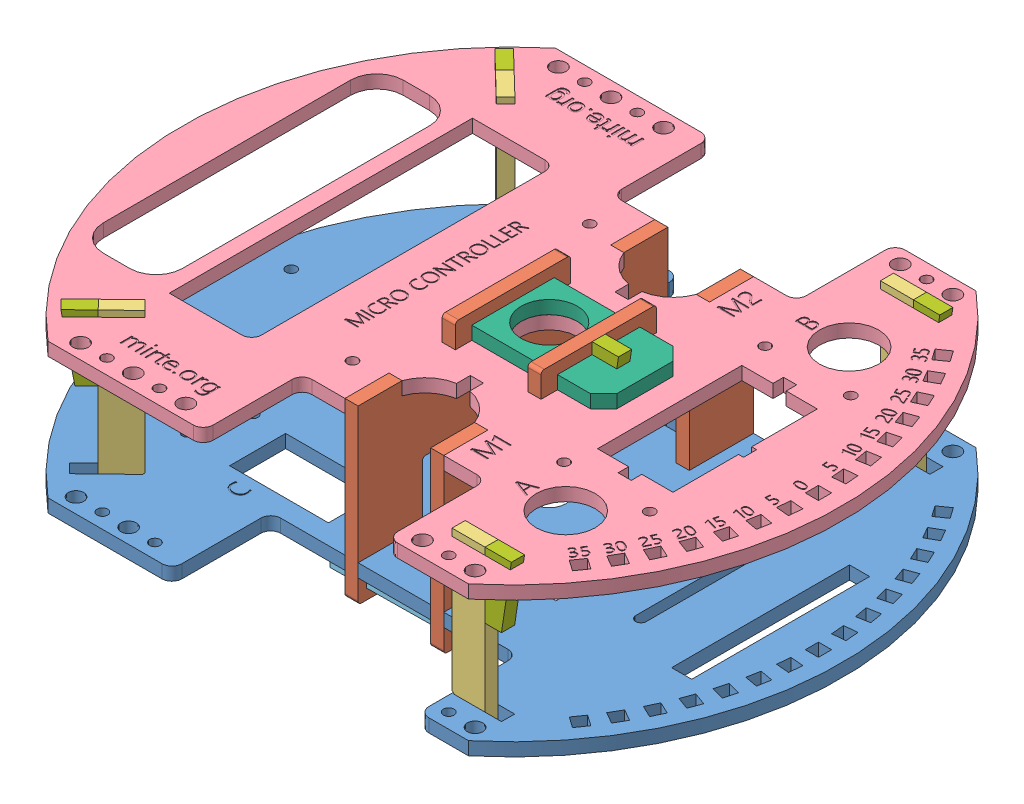
SolidWorks assembly Frame Only, configuration Default. Lengths in mm.
Overall size (200 59.7 154).
16 component instances, 7 part files, 47 mates.
Components (placement in the parent):
- LAYER 1 New-1: LAYER 1 New [Default] at origin size (200 4 154)
- Motor frame 2-1: Motor frame 2 [Default] at (22.3044 -7.1 47) x (0 0 -1) z (0 -1 0) size (94 4 59.7)
- Motor frame 2-2: Motor frame 2 [Default] at (-3.6956 -7.1 47) x (0 0 -1) z (0 -1 0) size (94 4 59.7)
- Slide spacer-1: Slide spacer [Default] at (-58.0581 21.9 53.2858) x (0.71934 0 -0.694658) z (0.694658 0 0.71934) size (10 50.4 4)
- Slide spacer-2: Slide spacer [Default] at (-55.2795 21.9 -56.1631) x (0.71934 0 0.694658) z (-0.694658 0 0.71934) size (10 50.4 4)
- Slide spacer-3: Slide spacer [Default] at (48.8044 22.1644 -63) x (-1 0 0) z (0 0 -1) size (10 50.4 4)
- Slide spacer-5: Slide spacer [Default] at (48.8044 22.1644 67) x (-1 0 0) z (0 0 -1) size (10 50.4 4)
- LAYER 2 new-1: LAYER 2 new [Default] at (-116.6328 -60.1337 -160.0612) size (200 4 154)
- Houder-1: Houder [Default] at (-10.6956 -4 -35.4978) size (45 4 9)
- Houder-2: Houder [Default] at (-10.6956 -4 44.4978) size (45 4 9)
- Pen Hole Lock-1: Pen Hole Lock [Default] at (-3.6956 45.2 12.5) size (44 4 25)
- WIG_single-1: WIG_single [Default] at (26.3044 32.6 2) x (-1 0 0) z (0 0 -1) size (8 20 4)
- WIG_single-2: WIG_single [Default] at (58.8044 27.3644 -63) x (-1 0 0) z (0 0 -1) size (8 20 4)
- WIG_single-3: WIG_single [Default] at (58.8044 27.3644 67) x (-1 0 0) z (0 0 -1) size (8 20 4)
- WIG_single-4: WIG_single [Default] at (-62.4729 27.1 -63.1097) x (0.71934 0 0.694658) z (-0.694658 0 0.71934) size (8 20 4)
- WIG_single-5: WIG_single [Default] at (-65.2515 27.1 60.2324) x (0.71934 0 -0.694658) z (0.694658 0 0.71934) size (8 20 4)
Mates (geometry in assembly coordinates):
- Coincident9: coincident aligned: plane of Motor frame 2-1 through (26.3044 -7.1 -47) normal (0 0 -1); plane of Motor frame 2-2 through (0.3044 -7.1 -47) normal (0 0 -1)
- Coincident10: coincident aligned: plane of Motor frame 2-1 through (26.3044 22 47) normal (0 -1 0); plane of Motor frame 2-2 through (0.3044 22 47) normal (0 -1 0)
- Coincident11: coincident anti-aligned: plane of LAYER 1 New-1 through (0 4 0) normal (0 1 0); plane of Motor frame 2-1 through (26.3044 4 47) normal (0 -1 0)
- Coincident12: coincident aligned: plane of LAYER 1 New-1 through (0 0 47) normal (0 0 1); plane of Motor frame 2-2 through (0.3044 -7.1 47) normal (0 0 1)
- Coincident13: coincident anti-aligned: plane of LAYER 1 New-1 through (0.3044 -14.5602 47.64) normal (-1 0 0); plane of Motor frame 2-2 through (0.3044 -7.1 47) normal (1 0 0)
- Coincident14: coincident anti-aligned: plane of LAYER 1 New-1 through (22.3044 -14.5602 47.64) normal (1 0 0); plane of Motor frame 2-1 through (22.3044 -7.1 47) normal (-1 0 0)
- Coincident29: coincident anti-aligned: plane of LAYER 1 New-1 through (-59.7394 -13.9983 60.47) normal (-0.71934 0 0.694658); plane of Slide spacer-1 through (-59.7394 21.9 60.47) normal (0.71934 0 -0.694658)
- Coincident30: coincident: line of LAYER 1 New-1 through (-66.9328 4 67.4166) axis (0.71934 0 -0.694658); plane of Slide spacer-1 through (-55.2795 21.9 56.1631) normal (0.694658 0 0.71934)
- Coincident31: coincident: point of LAYER 1 New-1; line of Slide spacer-1 through (-59.7394 0 60.47) axis (-0.694658 0 -0.71934)
- Coincident32: coincident anti-aligned: line of LAYER 1 New-1 through (-59.7394 0 -60.47) axis (-0.694658 0 0.71934); line of Slide spacer-2 through (-62.5181 0 -57.5927) axis (0.694658 0 -0.71934)
- Coincident33: coincident anti-aligned: plane of LAYER 1 New-1 through (-62.5181 -13.9983 -57.5927) normal (-0.71934 0 -0.694658); plane of Slide spacer-2 through (-62.5181 21.9 -57.5927) normal (0.71934 0 0.694658)
- Coincident34: coincident: line of LAYER 1 New-1 through (-69.7115 4 -64.5392) axis (0.71934 0 0.694658); plane of Slide spacer-2 through (-58.0581 21.9 -53.2858) normal (-0.694658 0 0.71934)
- Coincident35: coincident aligned: plane of LAYER 1 New-1 through (48.8044 0 0) normal (-1 0 0); plane of Slide spacer-5 through (48.8044 22.1644 63) normal (-1 0 0)
- Coincident36: coincident anti-aligned: plane of LAYER 1 New-1 through (53.8044 -13.9983 67) normal (0 0 -1); plane of Slide spacer-5 through (48.8044 22.1644 67) normal (0 0 1)
- Coincident39: coincident: plane of LAYER 1 New-1 through (0 0 0) normal (0 -1 0); line of Slide spacer-5 through (49.54 0 63) axis (0 0 1)
- Coincident40: coincident aligned: plane of LAYER 1 New-1 through (48.8044 0 0) normal (-1 0 0); plane of Slide spacer-3 through (48.8044 22.1644 -67) normal (-1 0 0)
- Coincident42: coincident anti-aligned: plane of LAYER 1 New-1 through (53.8044 -13.9983 -67) normal (0 0 1); plane of Slide spacer-3 through (48.8044 22.1644 -67) normal (0 0 -1)
- Coincident43: coincident: plane of LAYER 1 New-1 through (0 0 0) normal (0 -1 0); line of Slide spacer-3 through (49.54 0 -67) axis (0 0 1)
- Coincident44: coincident anti-aligned: plane of Motor frame 2-1 through (22.3044 -7.1 47) normal (-1 0 0); plane of LAYER 2 new-1 through (22.3044 45.2 -160.0612) normal (1 0 0)
- Coincident45: coincident anti-aligned: plane of Motor frame 2-1 through (26.3044 -7.1 17.5) normal (0 0 1); plane of LAYER 2 new-1 through (-116.6328 45.2 17.5) normal (0 0 -1)
- Coincident46: coincident anti-aligned: plane of Motor frame 2-1 through (26.3044 41.2 -47) normal (0 1 0); plane of LAYER 2 new-1 through (-116.6328 41.2 -160.0612) normal (0 -1 0)
- Coincident47: coincident: line of Motor frame 2-2 through (-3.6956 -4.1 44.42) axis (0 1 0); plane of Houder-2 through (34.3044 0 43.9978) normal (0.01111 0 0.999938)
- Parallel1: parallel aligned: plane of Motor frame 2-2 through (-3.6956 -7.1 47) normal (-1 0 0); plane of Houder-2 through (-10.6956 0 35.4978) normal (-1 0 0)
- Coincident49: coincident anti-aligned: plane of LAYER 1 New-1 through (0 0 0) normal (0 -1 0); plane of Houder-2 through (-10.6956 0 44.4978) normal (0 1 0)
- Distance1: distance = 7 mm aligned: plane of Houder-2 through (-10.6956 0 35.4978) normal (-1 0 0); plane of Motor frame 2-2 through (-3.6956 -7.1 47) normal (-1 0 0)
- Coincident51: coincident aligned: plane of Houder-1 through (-10.6956 0 -44.4978) normal (-1 0 0); plane of Houder-2 through (-10.6956 0 35.4978) normal (-1 0 0)
- Coincident52: coincident: line of Motor frame 2-2 through (-3.6956 -4.1 -44.42) axis (0 1 0); plane of Houder-1 through (-10.6956 0 -44.4978) normal (0.01111 0 -0.999938)
- Coincident53: coincident anti-aligned: plane of LAYER 1 New-1 through (0 0 0) normal (0 -1 0); plane of Houder-1 through (-10.6956 0 -35.4978) normal (0 1 0)
- Coincident54: coincident: line of Motor frame 2-1 through (26.3044 49.2 -12.5) axis (0 0 1); plane of Pen Hole Lock-1 through (-3.6956 49.2 12.5) normal (0 1 0)
- Coincident55: coincident anti-aligned: plane of Motor frame 2-1 through (26.3044 -7.1 -12.5) normal (0 0 1); plane of Pen Hole Lock-1 through (-3.6956 49.2 -12.5) normal (0 0 -1)
- Coincident56: coincident aligned: plane of Motor frame 2-1 through (26.3044 -7.1 47) normal (1 0 0); plane of Pen Hole Lock-1 through (26.3044 49.2 2) normal (1 0 0)
- Coincident57: coincident anti-aligned: plane of Pen Hole Lock-1 through (26.3044 49.2 2) normal (1 0 0); plane of WIG_single-1 through (26.3044 52.6 -2) normal (-1 0 0)
- Coincident58: coincident anti-aligned: plane of Pen Hole Lock-1 through (26.3044 49.2 2) normal (0 0 -1); plane of WIG_single-1 through (26.3044 32.6 2) normal (0 0 1)
- Coincident59: coincident aligned: plane of Motor frame 2-1 through (26.3044 52.6 47) normal (0 1 0); plane of WIG_single-1 through (34.3044 52.6 -2) normal (0 1 0)
- Coincident60: coincident anti-aligned: plane of Slide spacer-1 through (-62.4729 21.9 63.1097) normal (-0.71934 0 0.694658); plane of WIG_single-5 through (-62.4729 47.1 63.1097) normal (0.71934 0 -0.694658)
- Coincident61: coincident aligned: plane of Slide spacer-1 through (-55.2795 21.9 56.1631) normal (0.694658 0 0.71934); plane of WIG_single-5 through (-62.4729 27.1 63.1097) normal (0.694658 0 0.71934)
- Coincident62: coincident aligned: plane of Slide spacer-1 through (-55.2795 47.1 56.1631) normal (0 1 0); plane of WIG_single-5 through (-68.2276 47.1 68.667) normal (0 1 0)
- Coincident63: coincident anti-aligned: plane of Slide spacer-2 through (-65.2515 21.9 -60.2324) normal (-0.71934 0 -0.694658); plane of WIG_single-4 through (-65.2515 47.1 -60.2324) normal (0.71934 0 0.694658)
- Coincident64: coincident aligned: plane of Slide spacer-2 through (-58.0581 47.1 -53.2858) normal (0 1 0); plane of WIG_single-4 through (-71.0063 47.1 -65.7896) normal (0 1 0)
- Coincident65: coincident aligned: plane of Slide spacer-2 through (-55.2795 21.9 -56.1631) normal (0.694658 0 -0.71934); plane of WIG_single-4 through (-62.4729 27.1 -63.1097) normal (0.694658 0 -0.71934)
- Coincident66: coincident anti-aligned: plane of Slide spacer-3 through (58.8044 22.1644 -67) normal (1 0 0); plane of WIG_single-2 through (58.8044 47.3644 -67) normal (-1 0 0)
- Coincident67: coincident anti-aligned: plane of Slide spacer-3 through (58.8044 22.1644 -67) normal (1 0 0); plane of WIG_single-2 through (58.8044 47.3644 -67) normal (-1 0 0)
- Coincident68: coincident aligned: plane of Slide spacer-3 through (48.8044 22.1644 -63) normal (0 0 1); plane of WIG_single-2 through (58.8044 27.3644 -63) normal (0 0 1)
- Coincident69: coincident aligned: plane of Slide spacer-3 through (48.8044 47.3644 -67) normal (0 1 0); plane of WIG_single-2 through (66.8044 47.3644 -67) normal (0 1 0)
- Coincident70: coincident: plane of Slide spacer-5 through (58.8044 22.1644 63) normal (1 0 0); plane of WIG_single-3 through (58.8044 47.3644 63) normal (-1 0 0)
- Coincident72: coincident: plane of Slide spacer-5 through (48.8044 47.3644 63) normal (0 1 0); plane of WIG_single-3 through (66.8044 47.3644 63) normal (0 1 0)
- Coincident73: coincident: line of LAYER 2 new-1 through (53.0544 45.2 67) axis (1 0 0); plane of WIG_single-3 through (58.8044 27.3644 67) normal (0 0 1)
